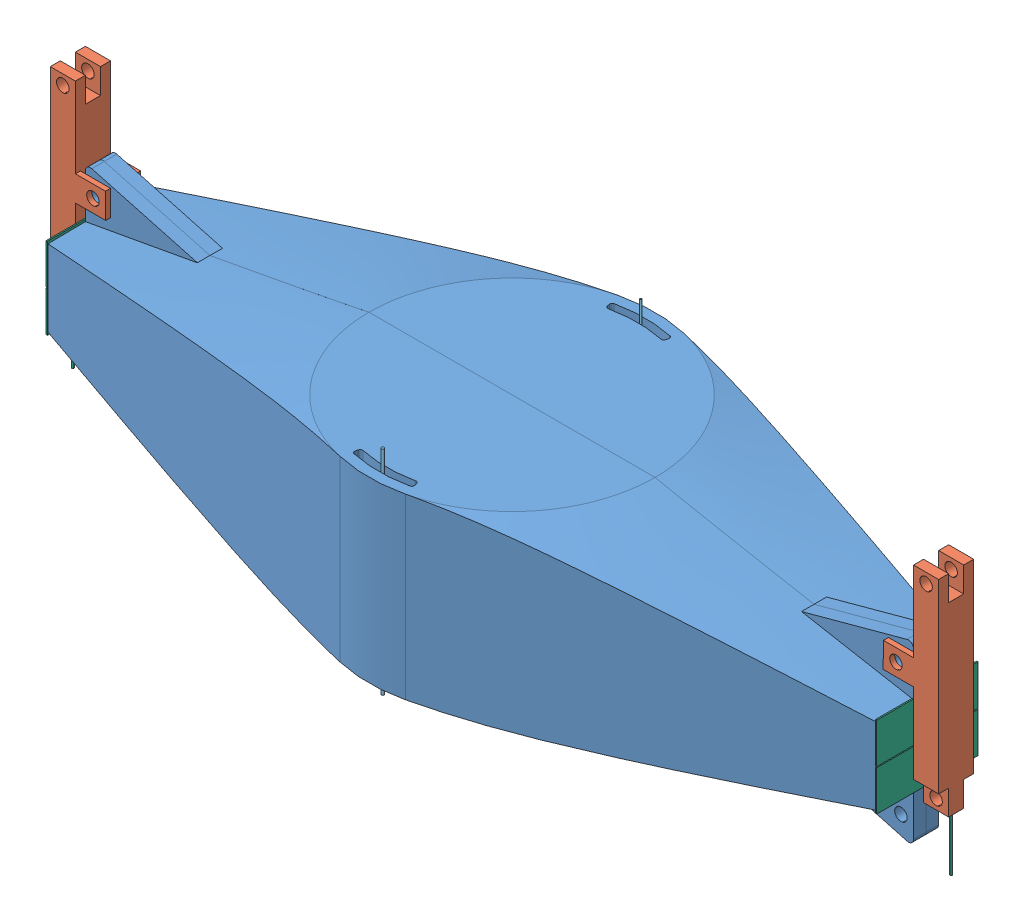
SolidWorks assembly RealUnit, configuration 默认. Lengths in mm.
Overall size (400 106.44 359.66).
10 component instances, 6 part files, 13 mates.
Components (placement in the parent):
- OuterShell-III-Part-6: OuterShell-III-Part [默认] at (-118.393 127.2935 -404.774) size (400 73.59 241.95)
- OuterShell-III-Part-7: OuterShell-III-Part [默认] at (-118.393 127.2935 -404.774) x (-1 0 0) z (0 0 -1) size (400 73.59 241.95)
- ConnectionRod-5: ConnectionRod [默认] at (-290.393 189.5608 -404.774) size (22.09 84 14)
- ConnectionRod-9: ConnectionRod [默认] at (53.607 189.5608 -404.774) x (-1 0 0) z (0 0 -1) size (22.09 84 14)
- InnerUnit-2: InnerUnit [默认] at (-116.4448 157.913 -484.774) x (-1 0 0) z (0 0 1) size (102 85 103.7)
  - BEGeDet-2: BEGeDet [默认] at (1.9481 14.6195 80) x (1 0 0) z (0 0 -1) size (80 40 80)
  - InnerShell-3: InnerShell [默认] at (1.9481 -36.3805 80) size (102 61 102)
  - Electronics-1: Electronics [默认] at (1.9481 24.7195 80) x (-1 0 0) z (0 0 1) size (21.21 85 103.7)
- SiPMArray-1: SiPMArray [默认] at (46.607 162.6183 -404.774) size (10.4 81 40.4)
- SiPMArray-2: SiPMArray [默认] at (-283.393 162.6183 -404.774) x (-1 0 0) z (0 0 -1) size (10.4 81 40.4)
Mates (geometry in assembly coordinates):
- 重合2: coincident aligned: circle of OuterShell-III-Part-6; circle of OuterShell-III-Part-7
- 重合3: coincident aligned: circle of OuterShell-III-Part-6; circle of OuterShell-III-Part-7
- 重合6: coincident aligned: circle of OuterShell-III-Part-6; circle of ConnectionRod-5
- 平行2: parallel anti-aligned: plane of OuterShell-III-Part-7 through (-283.393 279.2935 -424.6783) normal (-1 0 0); plane of ConnectionRod-5 through (-285.393 226.5608 -411.774) normal (1 0 0)
- 重合15: coincident aligned: circle of OuterShell-III-Part-6; circle of ConnectionRod-9
- 平行6: parallel anti-aligned: plane of OuterShell-III-Part-6 through (46.607 279.2935 -384.8698) normal (1 0 0); plane of ConnectionRod-9 through (48.607 226.5608 -397.774) normal (-1 0 0)
- 重合16: coincident anti-aligned: plane of OuterShell-III-Part-7 through (-118.393 194.2935 -404.774) normal (0 -1 0); plane of InnerUnit-2/InnerShell-3 through (-118.393 194.2935 -404.774) normal (0 1 0)
- 同心1: concentric aligned: circle of OuterShell-III-Part-7; circle of InnerUnit-2/InnerShell-3
- 重合17: coincident: point of SiPMArray-1; point of assembly
- 平行7: parallel anti-aligned: line of OuterShell-III-Part-7 through (46.607 195.6786 -409.774) axis (0 -1 0); line of SiPMArray-1 through (46.607 162.8183 -424.974) axis (0 1 0)
- 重合20: coincident: plane of OuterShell-III-Part-7 through (-283.393 279.2935 -424.6783) normal (-1 0 0); plane of SiPMArray-2 through (-283.393 162.7149 -404.774) normal (1 0 0)
- 重合21: coincident: plane of SiPMArray-1 through (47.107 162.8183 -424.974) normal (0 0 -1); plane of SiPMArray-2 through (-283.893 162.9149 -424.974) normal (0 0 -1)
- 重合22: coincident aligned: plane of SiPMArray-1 through (47.107 178.8183 -404.974) normal (0 1 0); plane of SiPMArray-2 through (-283.893 178.8183 -404.974) normal (0 1 0)
